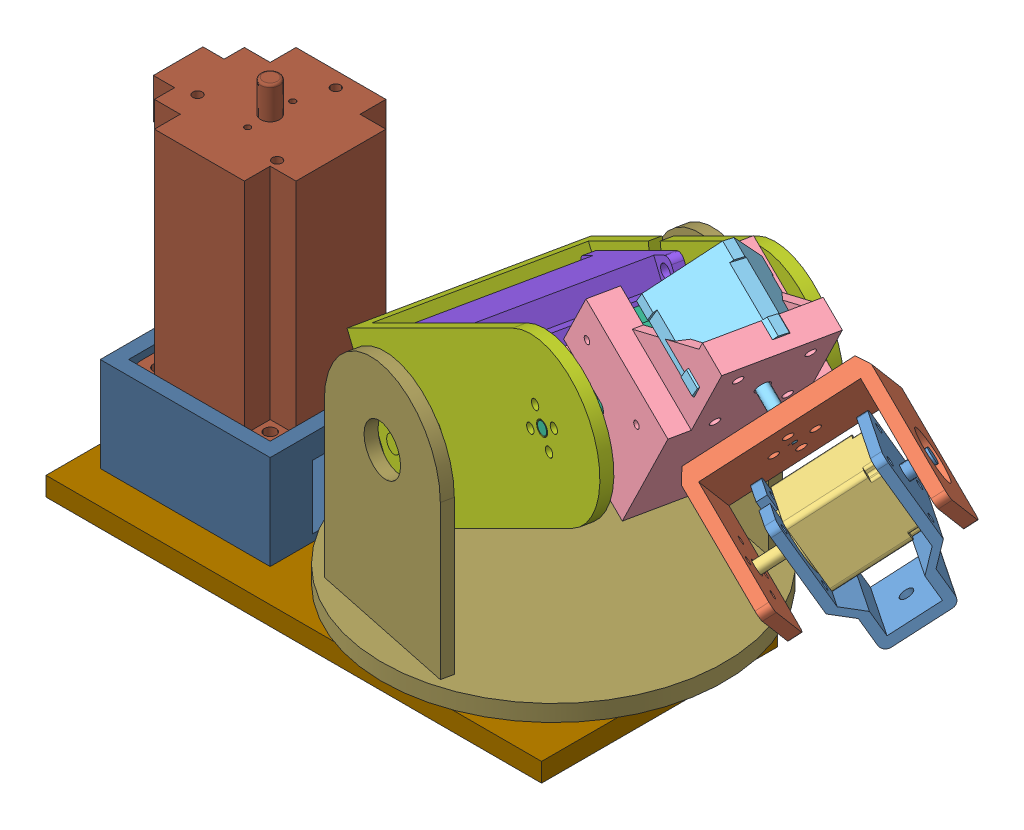
SolidWorks assembly AssemRobotArm, configuration Default. Lengths in mm.
Overall size (353.34 250.7 171.59).
12 component instances, 12 part files, 28 mates.
Components (placement in the parent):
- bao_de_nema11-1: bao_de_nema11 [Default] at (190.5812 39.945 -410.2254) x (0.420536 -0.846789 -0.325727) z (0.441826 0.504709 -0.74166) size (55.27 34.2 52)
- nap_baodenema11-1: nap_baodenema11 [Default] at (175.5014 45.2234 -473.5949) x (-0.441826 -0.504709 0.74166) z (-0.855384 0.486186 -0.178718) size (68 34.2 54)
- nema11-1: nema11 [Default] at (199.2439 39.7526 -451.0389) x (0.420536 -0.846789 -0.325727) z (-0.792426 -0.16798 -0.586381) size (28.2 54 28.2)
- deChua17va14-1: deChua17va14 [Default] at (103.06 62.0707 -479.9953) x (0.855384 -0.486186 0.178718) z (0.204517 0 -0.978863) size (51.3 85.5 70)
- nema14-1: nema14 [Default] at (116.16 71.8594 -451.7185) x (-0.449358 -0.524851 0.722917) z (0.257672 0.69868 0.667421) size (35.2 59.8 35.2)
- nema17-1: nema17 [Default] at (111.4358 30.5857 -476.2022) x (-0.47591 -0.873855 -0.099433) z (-0.855384 0.486186 -0.178718) size (42.3 73 43.3)
- chuanema17O2-1: chuanema17O2 [Default] at (45.563 -45.3526 -499.6703) x (-0.498616 0.86054 -0.104178) z (0.204517 0 -0.978863) size (63.3 136.95 102.5)
- nema23-1: nema23 [Default] at (39.0703 -4.8654 -422.875) x (0.842351 0.509383 0.175995) z (-0.498616 0.86054 -0.104178) size (64 98.5 57.3)
- de-1: de [Default] at (6.6886 -104.3714 -459.3376) size (210 8 100)
- de_chua_nema24-1: de_chua_nema24 [Default] at (-73.3114 -96.3714 -459.3376) x (0 0 1) z (-1 0 0) size (72 50 72)
- nema24-1: nema24 [Default] at (-73.3114 -66.3714 -459.3376) x (0 0 -1) z (1 0 0) size (60 135.8 69)
- de_chuyen_dong tư nema24-1: de_chuyen_dong tư nema24 [Default] at (46.6886 -71.3714 -459.3376) x (0.204517 0 -0.978863) z (0 1 0) size (145 145 129.75)
Mates (geometry in assembly coordinates):
- Coincident1: coincident anti-aligned: plane of de-1 through (6.6886 -96.3714 -459.3376) normal (0 1 0); plane of de_chua_nema24-1 through (-73.3114 -96.3714 -459.3376) normal (0 -1 0)
- Concentric1: concentric aligned: cylinder of de-1 through (-96.8814 -112.8567 -459.3376) axis (0 1 0) radius 3; cylinder of de_chua_nema24-1 through (-96.8814 -106.3714 -459.3376) axis (0 1 0) radius 3
- Concentric2: concentric aligned: cylinder of de-1 through (-73.3114 -112.8567 -482.9076) axis (0 1 0) radius 3; cylinder of de_chua_nema24-1 through (-73.3114 -106.3714 -482.9076) axis (0 1 0) radius 3
- Coincident2: coincident anti-aligned: plane of de_chua_nema24-1 through (-73.3114 -66.3714 -459.3376) normal (0 1 0); plane of nema24-1 through (-73.3114 -66.3714 -459.3376) normal (0 -1 0)
- Concentric3: concentric aligned: cylinder of de_chua_nema24-1 through (-73.3114 -93.3714 -459.3376) axis (0 1 0) radius 19.075; cylinder of nema24-1 through (-73.3114 -68.1714 -459.3376) axis (0 1 0) radius 19.05
- Coincident3: coincident aligned: cylinder of de_chua_nema24-1 through (-49.7414 -103.4425 -482.9076) axis (0 1 0) radius 2.5; circle of nema24-1
- Coincident4: coincident aligned: plane of de-1 through (6.6886 -104.3714 -459.3376) normal (0 -1 0); plane of de_chuyen_dong tư nema24-1 through (46.6886 -104.3714 -459.3376) normal (0 -1 0)
- Concentric4: concentric anti-aligned: cylinder of de-1 through (46.6886 -39.8029 -459.3376) axis (0 -1 0) radius 20; cylinder of de_chuyen_dong tư nema24-1 through (46.6886 -104.3714 -459.3376) axis (0 1 0) radius 10
- Coincident7: coincident anti-aligned: plane of chuanema17O2-1 through (55.0362 -4.8928 -499.3256) normal (-0.204517 0 0.978863); plane of nema23-1 through (55.0431 -4.8654 -499.3242) normal (0.204517 0 -0.978863)
- Concentric13: concentric anti-aligned: cylinder of chuanema17O2-1 through (65.858 27.3963 -510.6513) axis (-0.204517 0 0.978863) radius 2.65; cylinder of nema23-1 through (60.3287 27.3963 -484.1865) axis (0.204517 0 -0.978863) radius 2.7
- Parallel8: parallel aligned: cylinder of chuanema17O2-1 through (57.7562 -4.8928 -512.344) axis (-0.204517 0 0.978863) radius 3.5; cylinder of nema23-1 through (59.2153 -4.8654 -519.293) axis (-0.204517 0 0.978863) radius 3
- Parallel9: parallel aligned: plane of chuanema17O2-1 through (66.6108 38.4653 -500.3807) normal (-0.498616 0.86054 -0.104178); plane of nema23-1 through (16.2972 5.1952 -505.7849) normal (-0.498616 0.86054 -0.104178)
- Concentric19: concentric anti-aligned: cylinder of nema23-1 through (59.2153 -4.8654 -519.293) axis (-0.204517 0 0.978863) radius 3; cylinder of de_chuyen_dong tư nema24-1 through (56.1681 -4.8654 -504.7084) axis (0.204517 0 -0.978863) radius 3.5
- Coincident9: coincident aligned: plane of nema23-1 through (59.2153 -4.8654 -519.293) normal (0.204517 0 -0.978863); plane of de_chuyen_dong tư nema24-1 through (28.1364 -6.3714 -525.7864) normal (0.204517 0 -0.978863)
- Coincident10: coincident anti-aligned: plane of deChua17va14-1 through (101.21 30.5857 -427.259) normal (0.204517 0 -0.978863); plane of nema17-1 through (101.21 30.5857 -427.259) normal (-0.204517 0 0.978863)
- Concentric20: concentric aligned: cylinder of deChua17va14-1 through (98.861 30.5857 -416.0165) axis (0.204517 0 -0.978863) radius 3; cylinder of nema17-1 through (96.5061 30.5857 -404.7452) axis (0.204517 0 -0.978863) radius 2.5
- Parallel10: parallel aligned: plane of deChua17va14-1 through (69.777 21.6112 -430.7616) normal (-0.855384 0.486186 -0.178718); plane of nema17-1 through (93.5931 59.3506 -430.8936) normal (-0.855384 0.486186 -0.178718)
- Coincident12: coincident aligned: plane of nema17-1 through (96.5061 30.5857 -404.7452) normal (-0.204517 0 0.978863); plane of chuanema17O2-1 through (23.5878 -50.2884 -419.9802) normal (-0.204517 0 0.978863)
- Concentric21: concentric anti-aligned: cylinder of nema17-1 through (96.5061 30.5857 -404.7452) axis (0.204517 0 -0.978863) radius 2.5; cylinder of chuanema17O2-1 through (99.2641 30.5857 -417.9454) axis (-0.204517 0 0.978863) radius 3
- Coincident13: coincident anti-aligned: plane of deChua17va14-1 through (147.6382 53.9677 -445.1416) normal (-0.855384 0.486186 -0.178718); plane of nema14-1 through (147.6382 53.9677 -445.1416) normal (0.855384 -0.486186 0.178718)
- Concentric22: concentric aligned: cylinder of deChua17va14-1 through (157.4625 48.3837 -443.089) axis (-0.855384 0.486186 -0.178718) radius 3; cylinder of nema14-1 through (167.312 42.7854 -441.0311) axis (-0.855384 0.486186 -0.178718) radius 2.5
- Coincident14: coincident aligned: plane of nap_baodenema11-1 through (184.7485 69.6206 -451.4836) normal (0.855384 -0.486186 0.178718); plane of nema14-1 through (167.312 42.7854 -441.0311) normal (0.855384 -0.486186 0.178718)
- Concentric23: concentric anti-aligned: cylinder of nap_baodenema11-1 through (156.4855 48.939 -443.2931) axis (0.855384 -0.486186 0.178718) radius 1; cylinder of nema14-1 through (167.312 42.7854 -441.0311) axis (-0.855384 0.486186 -0.178718) radius 2.5
- Coincident15: coincident anti-aligned: plane of bao_de_nema11-1 through (183.78 22.0878 -425.0808) normal (0.441826 0.504709 -0.74166); plane of nema11-1 through (183.78 22.0878 -425.0808) normal (-0.441826 -0.504709 0.74166)
- Concentric24: concentric anti-aligned: cylinder of bao_de_nema11-1 through (187.9709 26.8751 -432.1157) axis (-0.441826 -0.504709 0.74166) radius 3; cylinder of nema11-1 through (175.3853 12.4983 -410.9893) axis (0.441826 0.504709 -0.74166) radius 2.5
- Parallel11: parallel aligned: plane of bao_de_nema11-1 through (163.4802 34.2001 -430.2797) normal (-0.420536 0.846789 0.325727); plane of nema11-1 through (189.9073 37.4054 -413.7034) normal (-0.420536 0.846789 0.325727)
- Coincident17: coincident aligned: plane of nap_baodenema11-1 through (197.1166 14.9731 -396.3593) normal (-0.441826 -0.504709 0.74166); circle of nema11-1
- Concentric25: concentric anti-aligned: cylinder of nap_baodenema11-1 through (181.3435 19.3045 -420.9908) axis (-0.441826 -0.504709 0.74166) radius 3; cylinder of nema11-1 through (175.3853 12.4983 -410.9893) axis (0.441826 0.504709 -0.74166) radius 2.5
